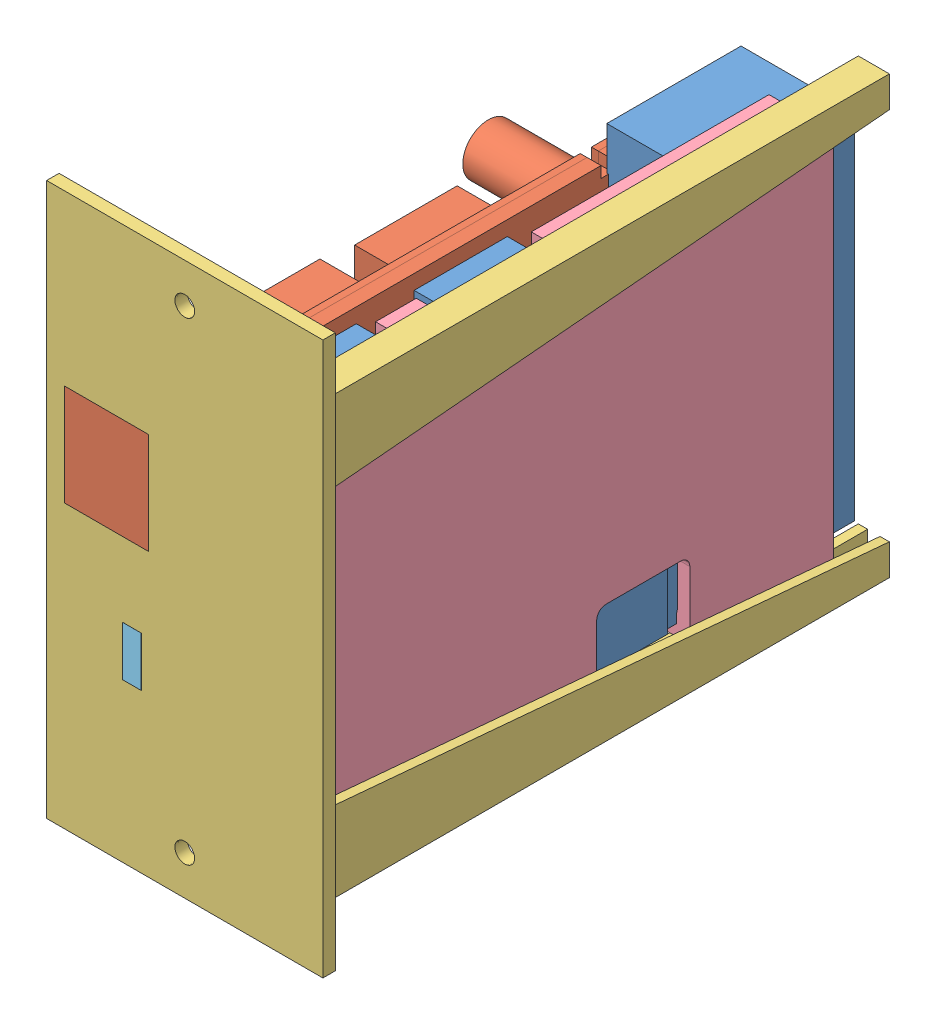
SolidWorks assembly Assem1, configuration Default. Lengths in mm.
Overall size (44.45 88.9 92.25).
6 component instances, 6 part files, 18 mates.
Components (placement in the parent):
- ODroid_C2.2-1: ODroid_C2.2 [Default] at (14 0 -47.5) x (0 0 1) z (-1 0 0) size (87.25 57.7 20.75)
- POE-1: POE [Default] at (-4.75 9.1044 -39.305) x (0 0 -1) z (-1 0 0) size (74.68 25.1 17.85)
- Rack_base-2: Rack_base [Default] x (-1 0 0) z (0 0 -1) size (44.45 88.9 92)
- Bracket-C2-1: Bracket-C2 [Default] at origin size (10.37 64.2 90)
- ODroid-UART-1: ODroid-UART [Default] at (-7 -15 -1) x (0 0 -1) z (0 1 0) size (27.15 6.5 13.57)
- POE-C2-bracket-1: POE-C2-bracket [Default] at (14 0 -47.5) x (0 -1 0) z (0 0 1) size (65.23 1 88.12)
Mates (geometry in assembly coordinates):
- Coincident12: coincident anti-aligned: plane of Rack_base-2 through (0 0 0) normal (-1 0 0); plane of assembly through (0 0 0) normal (1 0 0)
- Distance7: distance = 0 mm aligned: plane of Rack_base-2; plane of assembly through (0 0 0) normal (0 1 0)
- Coincident3: coincident anti-aligned: plane of Rack_base-2 through (0 0 0) normal (0 0 -1); plane of assembly through (0 0 0) normal (0 0 1)
- Distance1: distance = 5 mm anti-aligned: plane of Rack_base-2 through (0 0 0) normal (0 0 -1); plane of ODroid_C2.2-1 through (17.75 28 -5) normal (0 0 1)
- Distance6: distance = 14 mm aligned: plane of ODroid_C2.2-1 through (14 0 -47.5) normal (-1 0 0); plane of Rack_base-2 through (0 0 0) normal (-1 0 0)
- Coincident13: coincident aligned: plane of ODroid_C2.2-1; plane of Rack_base-2
- Distance2: distance = 10 mm: plane of POE-1; plane of ODroid_C2.2-1
- Distance3: distance = 18.75 mm aligned: plane of POE-1 through (-4.75 9.1044 -39.305) normal (-1 0 0); plane of ODroid_C2.2-1 through (14 0 -47.5) normal (-1 0 0)
- Coincident14: coincident anti-aligned: plane of Rack_base-2 through (0 0 0) normal (0 0 -1); plane of Bracket-C2-1 through (0 0 0) normal (0 0 1)
- Coincident15: coincident aligned: plane of Rack_base-2; plane of Bracket-C2-1 through (0 0 0) normal (0 1 0)
- Coincident16: coincident anti-aligned: plane of Rack_base-2 through (0 0 0) normal (-1 0 0); plane of Bracket-C2-1 through (0 0 0) normal (1 0 0)
- Coincident17: coincident aligned: plane of POE-1 through (-19.35 0.9544 0) normal (0 0 1); plane of Rack_base-2 through (0 0 0) normal (0 0 1)
- Distance10: distance = 15 mm aligned: plane of ODroid_C2.2-1; plane of ODroid-UART-1 through (-7 -15 -1) normal (0 1 0)
- Distance8: distance = 1 mm anti-aligned: plane of ODroid-UART-1; plane of Rack_base-2 through (0 0 0) normal (0 0 1)
- Distance11: distance = 21 mm aligned: plane of ODroid-UART-1; plane of ODroid_C2.2-1 through (14 0 -47.5) normal (-1 0 0)
- Coincident22: coincident anti-aligned: plane of ODroid_C2.2-1 through (14 0 -47.5) normal (-1 0 0); plane of POE-C2-bracket-1
- Coincident23: coincident aligned: plane of ODroid_C2.2-1 through (14 0 -47.5) normal (0 0 1); plane of POE-C2-bracket-1 through (14 0 -47.5) normal (0 0 1)
- Coincident24: coincident anti-aligned: plane of ODroid_C2.2-1; plane of POE-C2-bracket-1
